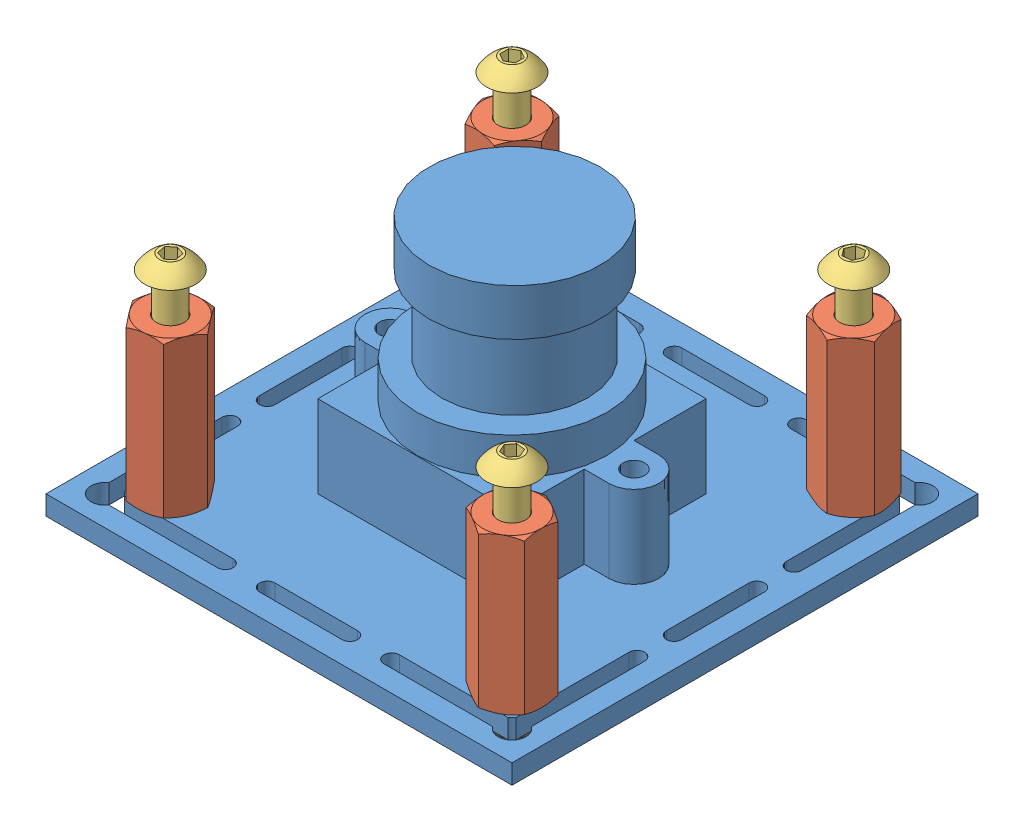
SolidWorks assembly ELP_cam_assembly_lightpanel, configuration Default. Lengths in mm.
Overall size (38.1 29.53 38.1).
13 component instances, 3 part files, 20 mates.
Components (placement in the parent):
- ELP_cam-1: ELP_cam [Default] at (259.2408 15.8942 -284.1444) size (38.1 29.53 38.1)
- 2-56 .5in  .1875 female-female standoff-2: 2-56 .5in  .1875 female-female standoff [91115A107] at (20.619 23.8317 45.4988) x (1 0 0) z (0 1 0) size (4.76 5.5 13.32)
- 2-56 .5in  .1875 female-female standoff-3: 2-56 .5in  .1875 female-female standoff [91115A107] at (20.619 23.8317 17.5588) x (0.982082 0 -0.188455) z (0 1 0) size (4.76 5.5 13.32)
- 2-56 .5in  .1875 female-female standoff-5: 2-56 .5in  .1875 female-female standoff [91115A107] at (-7.321 23.8317 17.5588) x (0.918365 0 -0.395734) z (0 1 0) size (4.76 5.5 13.32)
- 2-56 .5in  .1875 female-female standoff-7: 2-56 .5in  .1875 female-female standoff [91115A107] at (-7.321 23.8317 45.4988) x (0.8 0 -0.6) z (0 1 0) size (4.76 5.5 13.32)
- S-002-025-BTN-H-SS-001-256x1_4-button-head-screw-1: S-002-025-BTN-H-SS-001-256x1_4-button-head-screw [Default] at (-7.321 33.3567 17.5588) size (4.17 7.52 4.17)
- S-002-025-BTN-H-SS-001-256x1_4-button-head-screw-2: S-002-025-BTN-H-SS-001-256x1_4-button-head-screw [Default] at (-7.321 33.3567 45.4988) x (0.982082 0 -0.188455) z (0.188455 0 0.982082) size (4.17 7.52 4.17)
- S-002-025-BTN-H-SS-001-256x1_4-button-head-screw-4: S-002-025-BTN-H-SS-001-256x1_4-button-head-screw [Default] at (20.619 33.3567 45.4988) x (0.918365 0 -0.395734) z (0.395734 0 0.918365) size (4.17 7.52 4.17)
- S-002-025-BTN-H-SS-001-256x1_4-button-head-screw-6: S-002-025-BTN-H-SS-001-256x1_4-button-head-screw [Default] at (20.619 33.3567 17.5588) x (0.8 0 -0.6) z (0.6 0 0.8) size (4.17 7.52 4.17)
- S-002-025-BTN-H-SS-001-256x1_4-button-head-screw-11: S-002-025-BTN-H-SS-001-256x1_4-button-head-screw [Default] at (-7.321 15.8942 45.4988) x (-0.837169 0 -0.546944) z (-0.546944 0 0.837169) size (4.17 7.52 4.17)
- S-002-025-BTN-H-SS-001-256x1_4-button-head-screw-12: S-002-025-BTN-H-SS-001-256x1_4-button-head-screw [Default] at (-7.321 15.8942 17.5588) x (-0.925243 0 -0.379375) z (-0.379375 0 0.925243) size (4.17 7.52 4.17)
- S-002-025-BTN-H-SS-001-256x1_4-button-head-screw-13: S-002-025-BTN-H-SS-001-256x1_4-button-head-screw [Default] at (20.619 15.8942 17.5588) x (-0.985271 0 -0.170998) z (-0.170998 0 0.985271) size (4.17 7.52 4.17)
- S-002-025-BTN-H-SS-001-256x1_4-button-head-screw-14: S-002-025-BTN-H-SS-001-256x1_4-button-head-screw [Default] at (20.619 15.8942 45.4988) x (-0.997902 0 0.064746) z (0.064746 0 0.997902) size (4.17 7.52 4.17)
Mates (geometry in assembly coordinates):
- Coincident4: coincident anti-aligned: plane of ELP_cam-1 through (259.2408 17.4817 -284.1444) normal (0 1 0); plane of 2-56 .5in  .1875 female-female standoff-2 through (20.619 17.4817 42.7492) normal (0 -1 0)
- Coincident6: coincident anti-aligned: plane of ELP_cam-1 through (259.2408 17.4817 -284.1444) normal (0 1 0); plane of 2-56 .5in  .1875 female-female standoff-3 through (20.1009 17.4817 14.8584) normal (0 -1 0)
- Coincident7: coincident anti-aligned: plane of ELP_cam-1 through (259.2408 17.4817 -284.1444) normal (0 1 0); plane of 2-56 .5in  .1875 female-female standoff-5 through (-8.4091 17.4817 15.0336) normal (0 -1 0)
- Coincident8: coincident anti-aligned: plane of ELP_cam-1 through (259.2408 17.4817 -284.1444) normal (0 1 0); plane of 2-56 .5in  .1875 female-female standoff-7 through (-8.9707 17.4817 43.2991) normal (0 -1 0)
- Concentric7: concentric aligned: circle of 2-56 .5in  .1875 female-female standoff-5; cylinder of S-002-025-BTN-H-SS-001-256x1_4-button-head-screw-1 through (-7.321 27.0067 17.5588) axis (0 -1 0) radius 1.0922
- Distance1: distance = 3.175 mm anti-aligned: plane of 2-56 .5in  .1875 female-female standoff-5 through (-8.4091 30.1817 15.0336) normal (0 1 0); plane of S-002-025-BTN-H-SS-001-256x1_4-button-head-screw-1 through (-8.4132 33.3567 17.5588) normal (0 -1 0)
- Concentric8: concentric aligned: circle of 2-56 .5in  .1875 female-female standoff-7; cylinder of S-002-025-BTN-H-SS-001-256x1_4-button-head-screw-2 through (-7.321 27.0067 45.4988) axis (0 -1 0) radius 1.0922
- Distance2: distance = 3.175 mm anti-aligned: plane of 2-56 .5in  .1875 female-female standoff-7 through (-8.9707 30.1817 43.2991) normal (0 1 0); plane of S-002-025-BTN-H-SS-001-256x1_4-button-head-screw-2 through (-8.3936 33.3567 45.7046) normal (0 -1 0)
- Concentric9: concentric aligned: circle of 2-56 .5in  .1875 female-female standoff-2; cylinder of S-002-025-BTN-H-SS-001-256x1_4-button-head-screw-4 through (20.619 27.0067 45.4988) axis (0 -1 0) radius 1.0922
- Distance3: distance = 3.175 mm anti-aligned: plane of 2-56 .5in  .1875 female-female standoff-2 through (20.619 30.1817 42.7492) normal (0 1 0); plane of S-002-025-BTN-H-SS-001-256x1_4-button-head-screw-4 through (19.616 33.3567 45.931) normal (0 -1 0)
- Concentric10: concentric aligned: circle of 2-56 .5in  .1875 female-female standoff-3; cylinder of S-002-025-BTN-H-SS-001-256x1_4-button-head-screw-6 through (20.619 27.0067 17.5588) axis (0 -1 0) radius 1.0922
- Distance4: distance = 3.175 mm anti-aligned: plane of 2-56 .5in  .1875 female-female standoff-3 through (20.1009 30.1817 14.8584) normal (0 1 0); plane of S-002-025-BTN-H-SS-001-256x1_4-button-head-screw-6 through (19.7453 33.3567 18.2141) normal (0 -1 0)
- Concentric12: concentric aligned: cylinder of ELP_cam-1 through (-7.321 9.6077 45.4988) axis (0 1 0) radius 1.143; cylinder of S-002-025-BTN-H-SS-001-256x1_4-button-head-screw-11 through (-7.321 22.2442 45.4988) axis (0 1 0) radius 1.0922
- Coincident9: coincident anti-aligned: plane of ELP_cam-1 through (259.2408 15.8942 -284.1444) normal (0 -1 0); plane of S-002-025-BTN-H-SS-001-256x1_4-button-head-screw-11 through (-6.4066 15.8942 46.0962) normal (0 1 0)
- Coincident10: coincident anti-aligned: plane of ELP_cam-1 through (259.2408 15.8942 -284.1444) normal (0 -1 0); plane of S-002-025-BTN-H-SS-001-256x1_4-button-head-screw-12 through (-6.3104 15.8942 17.9731) normal (0 1 0)
- Concentric13: concentric aligned: cylinder of ELP_cam-1 through (-7.321 9.6077 17.5588) axis (0 1 0) radius 1.143; cylinder of S-002-025-BTN-H-SS-001-256x1_4-button-head-screw-12 through (-7.321 22.2442 17.5588) axis (0 1 0) radius 1.0922
- Coincident11: coincident anti-aligned: plane of ELP_cam-1 through (259.2408 15.8942 -284.1444) normal (0 -1 0); plane of S-002-025-BTN-H-SS-001-256x1_4-button-head-screw-13 through (21.6951 15.8942 17.7456) normal (0 1 0)
- Concentric14: concentric aligned: cylinder of ELP_cam-1 through (20.619 9.6077 17.5588) axis (0 1 0) radius 1.143; cylinder of S-002-025-BTN-H-SS-001-256x1_4-button-head-screw-13 through (20.619 22.2442 17.5588) axis (0 1 0) radius 1.0922
- Coincident12: coincident anti-aligned: plane of ELP_cam-1 through (259.2408 15.8942 -284.1444) normal (0 -1 0); plane of S-002-025-BTN-H-SS-001-256x1_4-button-head-screw-14 through (21.7089 15.8942 45.4281) normal (0 1 0)
- Concentric15: concentric aligned: cylinder of ELP_cam-1 through (20.619 9.6077 45.4988) axis (0 1 0) radius 1.143; cylinder of S-002-025-BTN-H-SS-001-256x1_4-button-head-screw-14 through (20.619 22.2442 45.4988) axis (0 1 0) radius 1.0922
